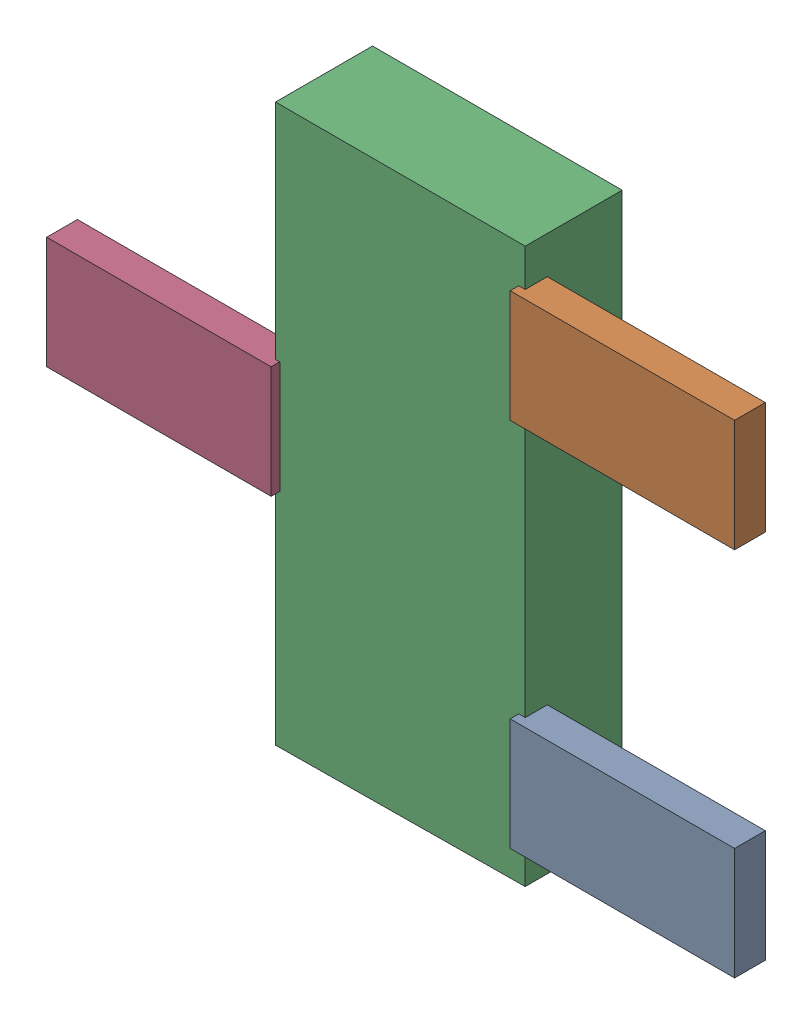
SolidWorks assembly VT1, configuration Default. Lengths in mm.
Overall size (3.58 2.9 0.55).
8 component instances, 2 part files, 0 mates.
Components (placement in the parent):
- 432134544_3-1: 432134544_3 [Default] at (33.9288 45.5927 -0.5715) size (1.17 0.58 0.16)
  - Extruded (38)-1: Extruded (38) [Default] at origin size (1.17 0.58 0.16)
- 432134544_4-1: 432134544_4 [Default] at (33.9288 47.5231 -0.5715) size (1.17 0.58 0.16)
  - Extruded (38)-1: Extruded (38) [Default] at origin size (1.17 0.58 0.16)
- 710423824_1-1: 710423824_1 [Default] at (32.728 46.5604 -0.9615) size (1.3 2.9 0.5)
  - Extruded (39)-1: Extruded (39) [Default] at origin size (1.3 2.9 0.5)
- 432134544_5-1: 432134544_5 [Default] at (31.5158 46.5579 -0.5715) size (1.17 0.58 0.16)
  - Extruded (38)-1: Extruded (38) [Default] at origin size (1.17 0.58 0.16)
